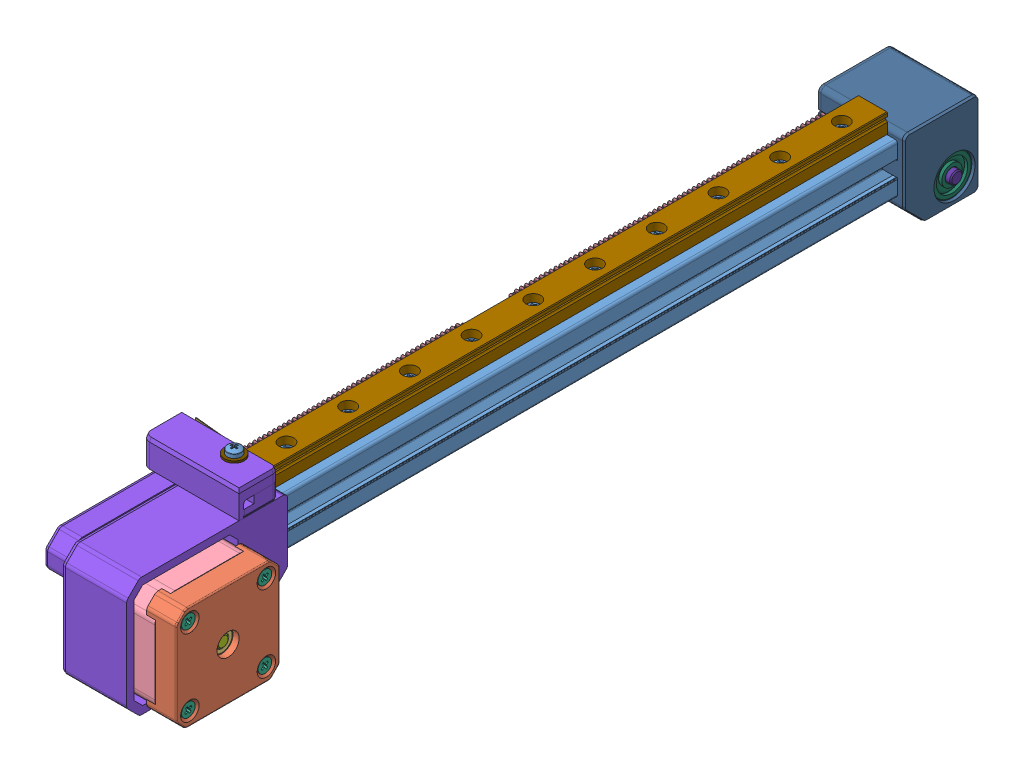
SolidWorks assembly Assem1, configuration По умолчанию. Lengths in mm.
Overall size (62 62.45 345.25).
59 component instances, 20 part files, 115 mates.
Components (placement in the parent):
- rsi_2020_274-1: rsi_2020_274 [По умолчанию] at origin size (20 20 274)
- 17HM15-0904S-1: 17HM15-0904S [По умолчанию] at (30 -11.15 303.15) x (0 0 -1) z (0 1 0) size (42.3 62 42.3)
  - nema17_bottom_40mm-1: nema17_bottom_40mm [По умолчанию] at origin size (42 12 42)
  - radial ball bearing_68_din-1: radial ball bearing_68_din [DIN 625 - 625 - 8,SI,NC,8_68] at (0 5 0) x (0 -1 0) z (0 0 1) size (5 16 16)
  - nema17_middle_40mm-1: nema17_middle_40mm [По умолчанию] at (0 8.5 0) size (42.3 23.5 42.3)
  - nema17_top_40mm-1: nema17_top_40mm [По умолчанию] at (0 32 0) size (42.3 12.6 42.3)
  - radial ball bearing_68_din-3: radial ball bearing_68_din [DIN 625 - 625 - 8,SI,NC,8_68] at (0 38.1 0) x (0 1 0) z (0 0 1) size (5 16 16)
  - countersunk flat head cross recess screw_din-1: countersunk flat head cross recess screw_din [ISO 7046-1 - M3 x 30 - Z --- 30N] at (15.5 0.6 15.5) x (0 1 0) z (0.546944 0 -0.837169) size (30 5.5 5.5)
  - countersunk flat head cross recess screw_din-2: countersunk flat head cross recess screw_din [ISO 7046-1 - M3 x 25 - Z --- 25N] at (15.5 0.6 -15.5) x (0 1 0) z (0.546944 0 -0.837169) size (25 5.5 5.5)
  - countersunk flat head cross recess screw_din-3: countersunk flat head cross recess screw_din [ISO 7046-1 - M3 x 30 - Z --- 30N] at (-15.5 0.6 15.5) x (0 1 0) z (0.546944 0 -0.837169) size (30 5.5 5.5)
  - countersunk flat head cross recess screw_din-4: countersunk flat head cross recess screw_din [ISO 7046-1 - M3 x 30 - Z --- 30N] at (-15.5 0.6 -15.5) x (0 1 0) z (0.546944 0 -0.837169) size (30 5.5 5.5)
  - nema17_shaft_40mm-1: nema17_shaft_40mm [По умолчанию] at (0 2 0) x (-0.412738 0 0.91085) z (-0.91085 0 -0.412738) size (5 60 5)
- nema17_mount_1-1: nema17_mount_1 [По умолчанию] at (-13 -10.7443 294.7873) x (0 0 -1) z (1 0 0) size (65.25 59.3 39.22)
- MGN12_250-1: MGN12_250 [По умолчанию] at (0 14 12) size (12 8 250)
- idle_pul_mount_1-1: idle_pul_mount_1 [По умолчанию] at (13 -3.403 -4.0666) x (0 0 1) z (-1 0 0) size (30 34 35)
- GT2_16T_13x14-1: GT2_16T_13x14 [Конфигурация1] at (-26.5 -11.15 303.15) x (1 0 0) z (0 0.386253 0.922393) size (14.1 13 13)
- GT2_16T_13x14-2: GT2_16T_13x14 [Конфигурация1] at (-26.5 -11.15 -8.1562) x (1 0 0) z (0 0.133178 -0.991092) size (14.1 13 13)
- SS-5GL_microswitch-2: SS-5GL_microswitch [Default] at (-42.2883 22.25 275.1397) x (0 -1 0) z (1 0 0) size (6.5 17.14 19.7)
- belt_250-1: belt_250 [По умолчанию] at (-19.83 -1.6143 147.7424) size (6 22.27 322.67)
- mgn12_fix-1: mgn12_fix [По умолчанию] at (0 12.9786 54.5) x (1 0 0) z (0 1 0) size (9.5 35 6)
- mgn12_fix-2: mgn12_fix [По умолчанию] at (0 12.9786 104.5) x (1 0 0) z (0 1 0) size (9.5 35 6)
- mgn12_fix-3: mgn12_fix [По умолчанию] at (0 12.9786 254.5) x (1 0 0) z (0 1 0) size (9.5 35 6)
- mgn12_fix-4: mgn12_fix [По умолчанию] at (0 12.9786 154.5) x (1 0 0) z (0 1 0) size (9.5 35 6)
- mgn12_fix-5: mgn12_fix [По умолчанию] at (0 12.9786 204.5) x (1 0 0) z (0 1 0) size (9.5 35 6)
- instrument ball bearing_68_am-1: instrument ball bearing_68_am [AFBMA 12.1.4.1 - 0050-16 - 8,SI,NC,8_68] at (-9.5 -11.15 -8.1562) size (5 16 16)
- instrument ball bearing_68_am-2: instrument ball bearing_68_am [AFBMA 12.1.4.1 - 0050-16 - 8,SI,NC,8_68] at (9.5 -11.15 -8.1562) size (5 16 16)
- socket head cap screw_am-1: socket head cap screw_am [B18.3.1M - 5 x 0.8 x 20 Hex SHCS -- 20NHX] at (0 0 280.85) x (0 0 -1) z (1 0 0) size (25 8.5 8.5)
- socket head cap screw_am-2: socket head cap screw_am [B18.3.1M - 5 x 0.8 x 20 Hex SHCS -- 20NHX] at (0 0 -11) x (0 0 1) z (-1 0 0) size (25 8.5 8.5)
- continous stud_am-1: continous stud_am [AM -- M5 x 45  N] at (-31 -11.15 -8.1562) size (45 5 5)
- plain washer 6902 type abc_din-1: plain washer 6902 type abc_din [DIN 6902-A3.2] at (-13 -26.65 318.65) x (-1 0 0) z (0 0.924225 0.381849) size (0.8 8 8)
- pan head cross recess screw_din-4: pan head cross recess screw_din [ISO 7045 - M3 x 6 - Z --- 6N] at (-16.2 -26.65 318.65) size (8.35 5.6 5.6)
- pan head cross recess screw_din-5: pan head cross recess screw_din [ISO 7045 - M3 x 6 - Z --- 6N] at (-16.2 -26.65 287.65) size (8.35 5.6 5.6)
- plain washer 6902 type abc_din-2: plain washer 6902 type abc_din [DIN 6902-A3.2] at (-13 -26.65 287.65) x (-1 0 0) z (0 0.924225 0.381849) size (0.8 8 8)
- pan head cross recess screw_din-6: pan head cross recess screw_din [ISO 7045 - M3 x 16 - Z --- 16N] at (-25.2 4.35 287.65) size (18.35 5.6 5.6)
- plain washer 6902 type abc_din-3: plain washer 6902 type abc_din [DIN 6902-A3.2] at (-22 4.35 287.65) x (-1 0 0) z (0 0.924225 0.381849) size (0.8 8 8)
- plain washer 6902 type abc_din-4: plain washer 6902 type abc_din [DIN 6902-A3.2] at (-22 4.35 318.65) x (-1 0 0) z (0 0.924225 0.381849) size (0.8 8 8)
- pan head cross recess screw_din-7: pan head cross recess screw_din [ISO 7045 - M3 x 20 - Z --- 20N] at (-25.2 4.35 318.65) size (22.35 5.6 5.6)
- pan head cross recess screw_din-9: pan head cross recess screw_din [ISO 7045 - M3 x 8 - Z --- 8N] at (0 15.9 24.5) x (0 -1 0) z (0 0 1) size (10.35 5.6 5.6)
- pan head cross recess screw_din-10: pan head cross recess screw_din [ISO 7045 - M3 x 8 - Z --- 8N] at (0 15.9 49.5) x (0 -1 0) z (-0.931961 0 -0.362559) size (10.35 5.6 5.6)
- hex nut style 1 gradeab_din-1: hex nut style 1 gradeab_din [Hexagon Nut ISO 4032 - M3 - D - N] at (0 5.1 24.5) x (0.5 0 0.866025) z (0 -1 0) size (5.5 6.35 2.4)
- hex nut style 1 gradeab_din-2: hex nut style 1 gradeab_din [Hexagon Nut ISO 4032 - M3 - D - N] at (0 5.1 49.5) x (0.5 0 0.866025) z (0 -1 0) size (5.5 6.35 2.4)
- hex nut style 1 gradeab_din-3: hex nut style 1 gradeab_din [Hexagon Nut ISO 4032 - M3 - D - N] at (0 5.1 99.5) x (0.5 0 0.866025) z (0 -1 0) size (5.5 6.35 2.4)
- hex nut style 1 gradeab_din-4: hex nut style 1 gradeab_din [Hexagon Nut ISO 4032 - M3 - D - N] at (0 5.1 74.5) x (0.5 0 0.866025) z (0 -1 0) size (5.5 6.35 2.4)
- pan head cross recess screw_din-11: pan head cross recess screw_din [ISO 7045 - M3 x 8 - Z --- 8N] at (0 15.9 74.5) x (0 -1 0) z (0 0 1) size (10.35 5.6 5.6)
- pan head cross recess screw_din-12: pan head cross recess screw_din [ISO 7045 - M3 x 8 - Z --- 8N] at (0 15.9 99.5) x (0 -1 0) z (-0.931961 0 -0.362559) size (10.35 5.6 5.6)
- hex nut style 1 gradeab_din-5: hex nut style 1 gradeab_din [Hexagon Nut ISO 4032 - M3 - D - N] at (0 5.1 249.5) x (0.5 0 0.866025) z (0 -1 0) size (5.5 6.35 2.4)
- hex nut style 1 gradeab_din-6: hex nut style 1 gradeab_din [Hexagon Nut ISO 4032 - M3 - D - N] at (0 5.1 224.5) x (0.5 0 0.866025) z (0 -1 0) size (5.5 6.35 2.4)
- pan head cross recess screw_din-13: pan head cross recess screw_din [ISO 7045 - M3 x 8 - Z --- 8N] at (0 15.9 224.5) x (0 -1 0) z (0 0 1) size (10.35 5.6 5.6)
- pan head cross recess screw_din-14: pan head cross recess screw_din [ISO 7045 - M3 x 8 - Z --- 8N] at (0 15.9 249.5) x (0 -1 0) z (-0.931961 0 -0.362559) size (10.35 5.6 5.6)
- hex nut style 1 gradeab_din-7: hex nut style 1 gradeab_din [Hexagon Nut ISO 4032 - M3 - D - N] at (0 5.1 149.5) x (0.5 0 0.866025) z (0 -1 0) size (5.5 6.35 2.4)
- hex nut style 1 gradeab_din-8: hex nut style 1 gradeab_din [Hexagon Nut ISO 4032 - M3 - D - N] at (0 5.1 124.5) x (0.5 0 0.866025) z (0 -1 0) size (5.5 6.35 2.4)
- pan head cross recess screw_din-15: pan head cross recess screw_din [ISO 7045 - M3 x 8 - Z --- 8N] at (0 15.9 124.5) x (0 -1 0) z (0 0 1) size (10.35 5.6 5.6)
- pan head cross recess screw_din-16: pan head cross recess screw_din [ISO 7045 - M3 x 8 - Z --- 8N] at (0 15.9 149.5) x (0 -1 0) z (-0.931961 0 -0.362559) size (10.35 5.6 5.6)
- hex nut style 1 gradeab_din-9: hex nut style 1 gradeab_din [Hexagon Nut ISO 4032 - M3 - D - N] at (0 5.1 199.5) x (0.5 0 0.866025) z (0 -1 0) size (5.5 6.35 2.4)
- hex nut style 1 gradeab_din-10: hex nut style 1 gradeab_din [Hexagon Nut ISO 4032 - M3 - D - N] at (0 5.1 174.5) x (0.5 0 0.866025) z (0 -1 0) size (5.5 6.35 2.4)
- pan head cross recess screw_din-17: pan head cross recess screw_din [ISO 7045 - M3 x 8 - Z --- 8N] at (0 15.9 174.5) x (0 -1 0) z (0 0 1) size (10.35 5.6 5.6)
- pan head cross recess screw_din-18: pan head cross recess screw_din [ISO 7045 - M3 x 8 - Z --- 8N] at (0 15.9 199.5) x (0 -1 0) z (-0.931961 0 -0.362559) size (10.35 5.6 5.6)
- plain washer 6902 type abc_din-5: plain washer 6902 type abc_din [DIN 6902-A3.2] at (0 24 270.6521) x (0 1 0) z (0.924225 0 0.381849) size (0.8 8 8)
- pan head cross recess screw_din-23: pan head cross recess screw_din [ISO 7045 - M3 x 16 - Z --- 16N] at (0 27.2 270.6521) x (0 -1 0) z (0 0 1) size (18.35 5.6 5.6)
Mates (geometry in assembly coordinates):
- Concentric1: concentric aligned: cylinder of rsi_2020_274-1 through (0 0 274) axis (0 0 -1) radius 2.5; cylinder of nema17_mount_1-1 through (0 0 327.251) axis (0 0 -1) radius 3.1
- Coincident4: coincident anti-aligned: plane of rsi_2020_274-1 through (0 0 274) normal (0 0 1); plane of nema17_mount_1-1 through (-13 -10.7443 274) normal (0 0 -1)
- Parallel2: parallel aligned: plane of rsi_2020_274-1 through (10 0 274) normal (1 0 0); plane of nema17_mount_1-1 through (13 -10.7443 294.7873) normal (1 0 0)
- Concentric2: concentric anti-aligned: cylinder of 17HM15-0904S-1/nema17_top_40mm-1 through (-12 -11.15 303.15) axis (1 0 0) radius 11; cylinder of nema17_mount_1-1 through (-10 -11.15 303.15) axis (-1 0 0) radius 11.05
- Coincident6: coincident anti-aligned: plane of 17HM15-0904S-1/nema17_top_40mm-1 through (-10 -11.15 303.15) normal (-1 0 0); plane of nema17_mount_1-1 through (-10 -10.7443 294.7873) normal (1 0 0)
- Parallel3: parallel aligned: plane of 17HM15-0904S-1/nema17_middle_40mm-1 through (-2 10 317.5735) normal (0 1 0); plane of nema17_mount_1-1 through (13 13 294.7873) normal (0 1 0)
- Coincident10: coincident anti-aligned: plane of rsi_2020_274-1 through (0 10 274) normal (0 1 0); plane of MGN12_250-1 through (-5.7 10 262) normal (0 -1 0)
- Coincident11: coincident anti-aligned: plane of nema17_mount_1-1 through (13 -10.7443 262) normal (0 0 -1); plane of MGN12_250-1 through (6.3091 15.5 262) normal (0 0 1)
- Distance2: distance = 4 mm aligned: plane of MGN12_250-1 through (-6 10.3 262) normal (-1 0 0); plane of rsi_2020_274-1 through (-10 0 274) normal (-1 0 0)
- Concentric5: concentric anti-aligned: cylinder of rsi_2020_274-1 through (0 0 274) axis (0 0 -1) radius 2.5; cylinder of idle_pul_mount_1-1 through (0 0 -18.001) axis (0 0 1) radius 3.1
- Coincident14: coincident anti-aligned: plane of rsi_2020_274-1 through (0 0 0) normal (0 0 -1); plane of idle_pul_mount_1-1 through (13 -3.403 0) normal (0 0 1)
- Concentric6: concentric aligned: cylinder of 17HM15-0904S-1/nema17_shaft_40mm-1 through (-32 -11.15 303.15) axis (1 0 0) radius 2.5; cylinder of GT2_16T_13x14-1 through (-26.5 -11.15 303.15) axis (1 0 0) radius 2.5
- Coincident15: coincident anti-aligned: plane of idle_pul_mount_1-1 through (-7 -11.15 -8.1562) normal (-1 0 0); plane of instrument ball bearing_68_am-1 through (-7 -3.45 -8.1562) normal (1 0 0)
- Concentric7: concentric anti-aligned: cylinder of idle_pul_mount_1-1 through (-7 -11.15 -8.1562) axis (-1 0 0) radius 8; cylinder of instrument ball bearing_68_am-1 through (-30.1375 -11.15 -8.1562) axis (1 0 0) radius 8
- Coincident16: coincident aligned: circle of idle_pul_mount_1-1; plane of instrument ball bearing_68_am-2 through (7 -4.8 -8.1562) normal (-1 0 0)
- Concentric8: concentric aligned: cylinder of idle_pul_mount_1-1 through (7 -11.15 -8.1562) axis (1 0 0) radius 8; cylinder of instrument ball bearing_68_am-2 through (-11.1375 -11.15 -8.1562) axis (1 0 0) radius 8
- Concentric9: concentric anti-aligned: cylinder of idle_pul_mount_1-1 through (0 0 -18.001) axis (0 0 1) radius 3.1; cylinder of socket head cap screw_am-2 through (0 0 -42.75) axis (0 0 -1) radius 4.25
- Coincident17: coincident anti-aligned: plane of idle_pul_mount_1-1 through (0 0 -6) normal (0 0 -1); plane of socket head cap screw_am-2 through (0 4.25 -6) normal (0 0 1)
- Concentric10: concentric anti-aligned: cylinder of nema17_mount_1-1 through (0 0 327.251) axis (0 0 -1) radius 3.1; cylinder of socket head cap screw_am-1 through (0 0 312.6) axis (0 0 1) radius 2.5
- Coincident18: coincident anti-aligned: plane of nema17_mount_1-1 through (0 0 275.85) normal (0 0 1); plane of socket head cap screw_am-1 through (0 4.25 275.85) normal (0 0 -1)
- Concentric11: concentric anti-aligned: cylinder of instrument ball bearing_68_am-1 through (-30.1375 -11.15 -8.1562) axis (1 0 0) radius 2.5; cylinder of continous stud_am-1 through (-34.175 -11.15 -8.1562) axis (-1 0 0) radius 2.5
- Distance3: distance = 2 mm aligned: plane of continous stud_am-1 through (14 -8.65 -8.1562) normal (1 0 0); plane of instrument ball bearing_68_am-2 through (12 -8.35 -8.1562) normal (1 0 0)
- Concentric12: concentric anti-aligned: cylinder of continous stud_am-1 through (-34.175 -11.15 -8.1562) axis (-1 0 0) radius 2.5; cylinder of GT2_16T_13x14-2 through (-26.5 -11.15 -8.1562) axis (1 0 0) radius 2.5
- Coincident20: coincident aligned: plane of nema17_mount_1-1 through (13 13 294.7873) normal (0 1 0); plane of idle_pul_mount_1-1 through (-13 13 -4.0666) normal (0 1 0)
- Coincident21: coincident aligned: plane of GT2_16T_13x14-1 through (-26.5 -11.15 303.15) normal (-1 0 0); plane of GT2_16T_13x14-2 through (-26.5 -11.15 -8.1562) normal (-1 0 0)
- Distance4: distance = 0.5 mm anti-aligned: plane of GT2_16T_13x14-2 through (-20.33 -11.15 -8.1562) normal (1 0 0); plane of belt_250-1 through (-19.83 -5.8558 5.1368) normal (-1 0 0)
- Concentric32: concentric anti-aligned: cylinder of nema17_mount_1-1 through (-10 -26.65 318.65) axis (-1 0 0) radius 1.6; cylinder of plain washer 6902 type abc_din-1 through (-13.8 -26.65 318.65) axis (1 0 0) radius 1.6
- Coincident39: coincident anti-aligned: plane of nema17_mount_1-1 through (-13 -10.7443 294.7873) normal (-1 0 0); plane of plain washer 6902 type abc_din-1 through (-13 -26.65 318.65) normal (1 0 0)
- Coincident40: coincident anti-aligned: plane of plain washer 6902 type abc_din-1 through (-13.8 -26.65 318.65) normal (-1 0 0); plane of pan head cross recess screw_din-4 through (-13.8 -25.15 318.65) normal (1 0 0)
- Concentric41: concentric anti-aligned: cylinder of plain washer 6902 type abc_din-1 through (-13.8 -26.65 318.65) axis (1 0 0) radius 1.6; cylinder of pan head cross recess screw_din-4 through (-41.6 -26.65 318.65) axis (-1 0 0) radius 1.5
- Coincident47: coincident anti-aligned: plane of pan head cross recess screw_din-5 through (-13.8 -25.15 287.65) normal (1 0 0); plane of plain washer 6902 type abc_din-2 through (-13.8 -26.65 287.65) normal (-1 0 0)
- Concentric42: concentric anti-aligned: cylinder of pan head cross recess screw_din-5 through (-41.6 -26.65 287.65) axis (-1 0 0) radius 1.5; cylinder of plain washer 6902 type abc_din-2 through (-13.8 -26.65 287.65) axis (1 0 0) radius 1.6
- Concentric43: concentric anti-aligned: cylinder of nema17_mount_1-1 through (-10 -26.65 287.65) axis (-1 0 0) radius 1.6; cylinder of plain washer 6902 type abc_din-2 through (-13.8 -26.65 287.65) axis (1 0 0) radius 1.6
- Coincident48: coincident anti-aligned: plane of nema17_mount_1-1 through (-13 -10.7443 294.7873) normal (-1 0 0); plane of plain washer 6902 type abc_din-2 through (-13 -26.65 287.65) normal (1 0 0)
- Coincident49: coincident anti-aligned: plane of pan head cross recess screw_din-6 through (-22.8 5.85 287.65) normal (1 0 0); plane of plain washer 6902 type abc_din-3 through (-22.8 4.35 287.65) normal (-1 0 0)
- Concentric44: concentric anti-aligned: cylinder of pan head cross recess screw_din-6 through (-50.6 4.35 287.65) axis (-1 0 0) radius 1.5; cylinder of plain washer 6902 type abc_din-3 through (-22.8 4.35 287.65) axis (1 0 0) radius 1.6
- Concentric45: concentric anti-aligned: cylinder of nema17_mount_1-1 through (-10 4.35 287.65) axis (-1 0 0) radius 1.6; cylinder of plain washer 6902 type abc_din-3 through (-22.8 4.35 287.65) axis (1 0 0) radius 1.6
- Coincident50: coincident anti-aligned: plane of nema17_mount_1-1 through (-22 2 264) normal (-1 0 0); plane of plain washer 6902 type abc_din-3 through (-22 4.35 287.65) normal (1 0 0)
- Coincident51: coincident anti-aligned: plane of plain washer 6902 type abc_din-4 through (-22.8 4.35 318.65) normal (-1 0 0); plane of pan head cross recess screw_din-7 through (-22.8 5.85 318.65) normal (1 0 0)
- Concentric46: concentric anti-aligned: cylinder of plain washer 6902 type abc_din-4 through (-22.8 4.35 318.65) axis (1 0 0) radius 1.6; cylinder of pan head cross recess screw_din-7 through (-50.6 4.35 318.65) axis (-1 0 0) radius 1.5
- Concentric47: concentric anti-aligned: cylinder of nema17_mount_1-1 through (-10 4.35 318.65) axis (-1 0 0) radius 1.6; cylinder of plain washer 6902 type abc_din-4 through (-22.8 4.35 318.65) axis (1 0 0) radius 1.6
- Coincident52: coincident anti-aligned: plane of nema17_mount_1-1 through (-22 2 264) normal (-1 0 0); plane of plain washer 6902 type abc_din-4 through (-22 4.35 318.65) normal (1 0 0)
- Distance9: distance = 5.5 mm aligned: plane of GT2_16T_13x14-1 through (-26.5 -11.15 303.15) normal (-1 0 0); plane of 17HM15-0904S-1/nema17_shaft_40mm-1 through (-32 -11.15 303.15) normal (-1 0 0)
- Concentric50: concentric anti-aligned: cylinder of MGN12_250-1 through (0 10 24.5) axis (0 1 0) radius 1.75; cylinder of mgn12_fix-1 through (0 10.001 24.5) axis (0 -1 0) radius 1.6
- Concentric51: concentric anti-aligned: cylinder of MGN12_250-1 through (0 10 49.5) axis (0 1 0) radius 1.75; cylinder of mgn12_fix-1 through (0 10.001 49.5) axis (0 -1 0) radius 1.6
- Coincident55: coincident anti-aligned: plane of MGN12_250-1 through (-5.7 10 262) normal (0 -1 0); plane of mgn12_fix-1 through (-3 10 19.5) normal (0 1 0)
- Concentric54: concentric aligned: cylinder of MGN12_250-1 through (0 10 49.5) axis (0 1 0) radius 1.75; cylinder of pan head cross recess screw_din-10 through (0 41.3 49.5) axis (0 1 0) radius 2.8
- Coincident57: coincident anti-aligned: plane of MGN12_250-1 through (0 13.5 49.5) normal (0 1 0); plane of pan head cross recess screw_din-10 through (-0.5438 13.5 50.8979) normal (0 -1 0)
- Parallel6: parallel aligned: plane of mgn12_fix-1 through (-2.9 7.5 22.8257) normal (0.5 0 0.866025); plane of hex nut style 1 gradeab_din-1 through (0 7.5 27.6754) normal (0.5 0 0.866025)
- Coincident61: coincident anti-aligned: plane of mgn12_fix-1 through (0 7.5 54.5) normal (0 -1 0); plane of hex nut style 1 gradeab_din-1 through (-2.75 7.5 26.0877) normal (0 1 0)
- Concentric57: concentric anti-aligned: cylinder of pan head cross recess screw_din-10 through (0 41.3 49.5) axis (0 1 0) radius 1.5; cylinder of hex nut style 1 gradeab_din-2 through (0 7.5 49.5) axis (0 -1 0) radius 1.25
- Parallel7: parallel aligned: plane of mgn12_fix-1 through (0 7.5 46.1514) normal (0.5 0 0.866025); plane of hex nut style 1 gradeab_din-2 through (0 7.5 52.6754) normal (0.5 0 0.866025)
- Coincident62: coincident anti-aligned: plane of mgn12_fix-1 through (0 7.5 54.5) normal (0 -1 0); plane of hex nut style 1 gradeab_din-2 through (-2.75 7.5 51.0877) normal (0 1 0)
- Concentric59: concentric aligned: cylinder of MGN12_250-1 through (0 10 24.5) axis (0 1 0) radius 1.75; cylinder of pan head cross recess screw_din-9 through (0 41.3 24.5) axis (0 1 0) radius 1.5
- Coincident64: coincident anti-aligned: plane of MGN12_250-1 through (0 13.5 24.5) normal (0 1 0); plane of pan head cross recess screw_din-9 through (1.5 13.5 24.5) normal (0 -1 0)
- Concentric85: concentric anti-aligned: cylinder of pan head cross recess screw_din-9 through (0 41.3 24.5) axis (0 1 0) radius 1.5; cylinder of hex nut style 1 gradeab_din-1 through (0 7.5 24.5) axis (0 -1 0) radius 1.25
- Parallel16: parallel aligned: plane of mgn12_fix-2 through (-2.9 7.5 72.8257) normal (0.5 0 0.866025); plane of hex nut style 1 gradeab_din-4 through (0 7.5 77.6754) normal (0.5 0 0.866025)
- Coincident85: coincident anti-aligned: plane of mgn12_fix-2 through (0 7.5 104.5) normal (0 -1 0); plane of hex nut style 1 gradeab_din-4 through (-2.75 7.5 76.0877) normal (0 1 0)
- Concentric86: concentric anti-aligned: cylinder of hex nut style 1 gradeab_din-3 through (0 7.5 99.5) axis (0 -1 0) radius 1.25; cylinder of pan head cross recess screw_din-12 through (0 41.3 99.5) axis (0 1 0) radius 1.5
- Parallel17: parallel aligned: plane of mgn12_fix-2 through (0 7.5 96.1514) normal (0.5 0 0.866025); plane of hex nut style 1 gradeab_din-3 through (0 7.5 102.6754) normal (0.5 0 0.866025)
- Coincident86: coincident anti-aligned: plane of mgn12_fix-2 through (0 7.5 104.5) normal (0 -1 0); plane of hex nut style 1 gradeab_din-3 through (-2.75 7.5 101.0877) normal (0 1 0)
- Concentric87: concentric anti-aligned: cylinder of hex nut style 1 gradeab_din-4 through (0 7.5 74.5) axis (0 -1 0) radius 1.25; cylinder of pan head cross recess screw_din-11 through (0 41.3 74.5) axis (0 1 0) radius 1.5
- Concentric88: concentric anti-aligned: cylinder of MGN12_250-1 through (0 10 74.5) axis (0 1 0) radius 1.75; cylinder of mgn12_fix-2 through (0 10.001 74.5) axis (0 -1 0) radius 1.6
- Concentric89: concentric anti-aligned: cylinder of MGN12_250-1 through (0 10 99.5) axis (0 1 0) radius 1.75; cylinder of mgn12_fix-2 through (0 10.001 99.5) axis (0 -1 0) radius 1.6
- Coincident87: coincident anti-aligned: plane of MGN12_250-1 through (-5.7 10 262) normal (0 -1 0); plane of mgn12_fix-2 through (-3 10 69.5) normal (0 1 0)
- Concentric90: concentric aligned: cylinder of MGN12_250-1 through (0 10 99.5) axis (0 1 0) radius 1.75; cylinder of pan head cross recess screw_din-12 through (0 41.3 99.5) axis (0 1 0) radius 2.8
- Coincident88: coincident anti-aligned: plane of MGN12_250-1 through (0 13.5 49.5) normal (0 1 0); plane of pan head cross recess screw_din-12 through (-0.5438 13.5 100.8979) normal (0 -1 0)
- Concentric91: concentric aligned: cylinder of MGN12_250-1 through (0 10 74.5) axis (0 1 0) radius 1.75; cylinder of pan head cross recess screw_din-11 through (0 41.3 74.5) axis (0 1 0) radius 1.5
- Coincident89: coincident anti-aligned: plane of MGN12_250-1 through (0 13.5 24.5) normal (0 1 0); plane of pan head cross recess screw_din-11 through (1.5 13.5 74.5) normal (0 -1 0)
- Parallel18: parallel aligned: plane of mgn12_fix-3 through (-2.9 7.5 222.8257) normal (0.5 0 0.866025); plane of hex nut style 1 gradeab_din-6 through (0 7.5 227.6754) normal (0.5 0 0.866025)
- Coincident90: coincident anti-aligned: plane of mgn12_fix-3 through (0 7.5 254.5) normal (0 -1 0); plane of hex nut style 1 gradeab_din-6 through (-2.75 7.5 226.0877) normal (0 1 0)
- Concentric92: concentric anti-aligned: cylinder of hex nut style 1 gradeab_din-5 through (0 7.5 249.5) axis (0 -1 0) radius 1.25; cylinder of pan head cross recess screw_din-14 through (0 41.3 249.5) axis (0 1 0) radius 1.5
- Parallel19: parallel aligned: plane of mgn12_fix-3 through (0 7.5 246.1514) normal (0.5 0 0.866025); plane of hex nut style 1 gradeab_din-5 through (0 7.5 252.6754) normal (0.5 0 0.866025)
- Coincident91: coincident anti-aligned: plane of mgn12_fix-3 through (0 7.5 254.5) normal (0 -1 0); plane of hex nut style 1 gradeab_din-5 through (-2.75 7.5 251.0877) normal (0 1 0)
- Concentric93: concentric anti-aligned: cylinder of hex nut style 1 gradeab_din-6 through (0 7.5 224.5) axis (0 -1 0) radius 1.25; cylinder of pan head cross recess screw_din-13 through (0 41.3 224.5) axis (0 1 0) radius 1.5
- Concentric94: concentric anti-aligned: cylinder of MGN12_250-1 through (0 10 224.5) axis (0 1 0) radius 1.75; cylinder of mgn12_fix-3 through (0 10.001 224.5) axis (0 -1 0) radius 1.6
- Coincident92: coincident anti-aligned: plane of MGN12_250-1 through (-5.7 10 262) normal (0 -1 0); plane of mgn12_fix-3 through (-3 10 219.5) normal (0 1 0)
- Coincident93: coincident anti-aligned: plane of MGN12_250-1 through (0 13.5 49.5) normal (0 1 0); plane of pan head cross recess screw_din-14 through (-0.5438 13.5 250.8979) normal (0 -1 0)
- Coincident94: coincident anti-aligned: plane of MGN12_250-1 through (0 13.5 24.5) normal (0 1 0); plane of pan head cross recess screw_din-13 through (1.5 13.5 224.5) normal (0 -1 0)
- Concentric95: concentric anti-aligned: cylinder of MGN12_250-1 through (0 10 249.5) axis (0 1 0) radius 1.75; cylinder of mgn12_fix-3 through (0 10.001 249.5) axis (0 -1 0) radius 1.6
- Concentric96: concentric aligned: cylinder of MGN12_250-1 through (0 10 249.5) axis (0 1 0) radius 1.75; cylinder of pan head cross recess screw_din-14 through (0 41.3 249.5) axis (0 1 0) radius 2.8
- Concentric97: concentric aligned: cylinder of MGN12_250-1 through (0 10 224.5) axis (0 1 0) radius 1.75; cylinder of pan head cross recess screw_din-13 through (0 41.3 224.5) axis (0 1 0) radius 1.5
- Parallel20: parallel aligned: plane of mgn12_fix-4 through (-2.9 7.5 122.8257) normal (0.5 0 0.866025); plane of hex nut style 1 gradeab_din-8 through (0 7.5 127.6754) normal (0.5 0 0.866025)
- Coincident95: coincident anti-aligned: plane of mgn12_fix-4 through (0 7.5 154.5) normal (0 -1 0); plane of hex nut style 1 gradeab_din-8 through (-2.75 7.5 126.0877) normal (0 1 0)
- Concentric98: concentric anti-aligned: cylinder of hex nut style 1 gradeab_din-7 through (0 7.5 149.5) axis (0 -1 0) radius 1.25; cylinder of pan head cross recess screw_din-16 through (0 41.3 149.5) axis (0 1 0) radius 1.5
- Parallel21: parallel aligned: plane of mgn12_fix-4 through (0 7.5 146.1514) normal (0.5 0 0.866025); plane of hex nut style 1 gradeab_din-7 through (0 7.5 152.6754) normal (0.5 0 0.866025)
- Coincident96: coincident anti-aligned: plane of mgn12_fix-4 through (0 7.5 154.5) normal (0 -1 0); plane of hex nut style 1 gradeab_din-7 through (-2.75 7.5 151.0877) normal (0 1 0)
- Concentric99: concentric anti-aligned: cylinder of hex nut style 1 gradeab_din-8 through (0 7.5 124.5) axis (0 -1 0) radius 1.25; cylinder of pan head cross recess screw_din-15 through (0 41.3 124.5) axis (0 1 0) radius 1.5
- Concentric100: concentric anti-aligned: cylinder of MGN12_250-1 through (0 10 124.5) axis (0 1 0) radius 1.75; cylinder of mgn12_fix-4 through (0 10.001 124.5) axis (0 -1 0) radius 1.6
- Coincident97: coincident anti-aligned: plane of MGN12_250-1 through (-5.7 10 262) normal (0 -1 0); plane of mgn12_fix-4 through (-3 10 119.5) normal (0 1 0)
- Coincident98: coincident anti-aligned: plane of MGN12_250-1 through (0 13.5 49.5) normal (0 1 0); plane of pan head cross recess screw_din-16 through (-0.5438 13.5 150.8979) normal (0 -1 0)
- Coincident99: coincident anti-aligned: plane of MGN12_250-1 through (0 13.5 24.5) normal (0 1 0); plane of pan head cross recess screw_din-15 through (1.5 13.5 124.5) normal (0 -1 0)
- Concentric101: concentric anti-aligned: cylinder of MGN12_250-1 through (0 10 149.5) axis (0 1 0) radius 1.75; cylinder of mgn12_fix-4 through (0 10.001 149.5) axis (0 -1 0) radius 1.6
- Concentric102: concentric aligned: cylinder of MGN12_250-1 through (0 10 149.5) axis (0 1 0) radius 1.75; cylinder of pan head cross recess screw_din-16 through (0 41.3 149.5) axis (0 1 0) radius 2.8
- Concentric103: concentric aligned: cylinder of MGN12_250-1 through (0 10 124.5) axis (0 1 0) radius 1.75; cylinder of pan head cross recess screw_din-15 through (0 41.3 124.5) axis (0 1 0) radius 1.5
- Parallel22: parallel aligned: plane of mgn12_fix-5 through (-2.9 7.5 172.8257) normal (0.5 0 0.866025); plane of hex nut style 1 gradeab_din-10 through (0 7.5 177.6754) normal (0.5 0 0.866025)
- Coincident100: coincident anti-aligned: plane of mgn12_fix-5 through (0 7.5 204.5) normal (0 -1 0); plane of hex nut style 1 gradeab_din-10 through (-2.75 7.5 176.0877) normal (0 1 0)
- Concentric104: concentric anti-aligned: cylinder of hex nut style 1 gradeab_din-9 through (0 7.5 199.5) axis (0 -1 0) radius 1.25; cylinder of pan head cross recess screw_din-18 through (0 41.3 199.5) axis (0 1 0) radius 1.5
- Parallel23: parallel aligned: plane of mgn12_fix-5 through (0 7.5 196.1514) normal (0.5 0 0.866025); plane of hex nut style 1 gradeab_din-9 through (0 7.5 202.6754) normal (0.5 0 0.866025)
- Coincident101: coincident anti-aligned: plane of mgn12_fix-5 through (0 7.5 204.5) normal (0 -1 0); plane of hex nut style 1 gradeab_din-9 through (-2.75 7.5 201.0877) normal (0 1 0)
- Concentric105: concentric anti-aligned: cylinder of hex nut style 1 gradeab_din-10 through (0 7.5 174.5) axis (0 -1 0) radius 1.25; cylinder of pan head cross recess screw_din-17 through (0 41.3 174.5) axis (0 1 0) radius 1.5
- Concentric106: concentric anti-aligned: cylinder of MGN12_250-1 through (0 10 174.5) axis (0 1 0) radius 1.75; cylinder of mgn12_fix-5 through (0 10.001 174.5) axis (0 -1 0) radius 1.6
- Coincident102: coincident anti-aligned: plane of MGN12_250-1 through (-5.7 10 262) normal (0 -1 0); plane of mgn12_fix-5 through (-3 10 169.5) normal (0 1 0)
- Coincident103: coincident anti-aligned: plane of MGN12_250-1 through (0 13.5 49.5) normal (0 1 0); plane of pan head cross recess screw_din-18 through (-0.5438 13.5 200.8979) normal (0 -1 0)
- Coincident104: coincident anti-aligned: plane of MGN12_250-1 through (0 13.5 24.5) normal (0 1 0); plane of pan head cross recess screw_din-17 through (1.5 13.5 174.5) normal (0 -1 0)
- Concentric107: concentric anti-aligned: cylinder of MGN12_250-1 through (0 10 199.5) axis (0 1 0) radius 1.75; cylinder of mgn12_fix-5 through (0 10.001 199.5) axis (0 -1 0) radius 1.6
- Concentric108: concentric aligned: cylinder of MGN12_250-1 through (0 10 199.5) axis (0 1 0) radius 1.75; cylinder of pan head cross recess screw_din-18 through (0 41.3 199.5) axis (0 1 0) radius 2.8
- Concentric109: concentric aligned: cylinder of MGN12_250-1 through (0 10 174.5) axis (0 1 0) radius 1.75; cylinder of pan head cross recess screw_din-17 through (0 41.3 174.5) axis (0 1 0) radius 1.5
- Concentric118: concentric aligned: cylinder of nema17_mount_1-1 through (-9.5152 15.6 272.6147) axis (0 1 0) radius 1.275; cylinder of SS-5GL_microswitch-2 through (-9.5152 15.75 272.6147) axis (0 1 0) radius 1.275
- Concentric119: concentric aligned: cylinder of nema17_mount_1-1 through (-19.2152 15.6 272.6147) axis (0 1 0) radius 1.275; cylinder of SS-5GL_microswitch-2 through (-19.2152 15.75 272.6147) axis (0 1 0) radius 1.275
- Coincident113: coincident anti-aligned: plane of nema17_mount_1-1 through (-13 16 294.7873) normal (0 1 0); plane of SS-5GL_microswitch-2 through (-42.2883 16 275.1397) normal (0 -1 0)
- Coincident114: coincident anti-aligned: plane of plain washer 6902 type abc_din-5 through (0 24.8 270.6521) normal (0 1 0); plane of pan head cross recess screw_din-23 through (1.5 24.8 270.6521) normal (0 -1 0)
- Concentric120: concentric anti-aligned: cylinder of plain washer 6902 type abc_din-5 through (0 24.8 270.6521) axis (0 -1 0) radius 1.6; cylinder of pan head cross recess screw_din-23 through (0 52.6 270.6521) axis (0 1 0) radius 1.5
- Concentric121: concentric anti-aligned: cylinder of nema17_mount_1-1 through (0 3 270.6521) axis (0 1 0) radius 1.6; cylinder of plain washer 6902 type abc_din-5 through (0 24.8 270.6521) axis (0 -1 0) radius 1.6
- Coincident115: coincident anti-aligned: plane of nema17_mount_1-1 through (10.8 24 267.9147) normal (0 1 0); plane of plain washer 6902 type abc_din-5 through (0 24 270.6521) normal (0 -1 0)
